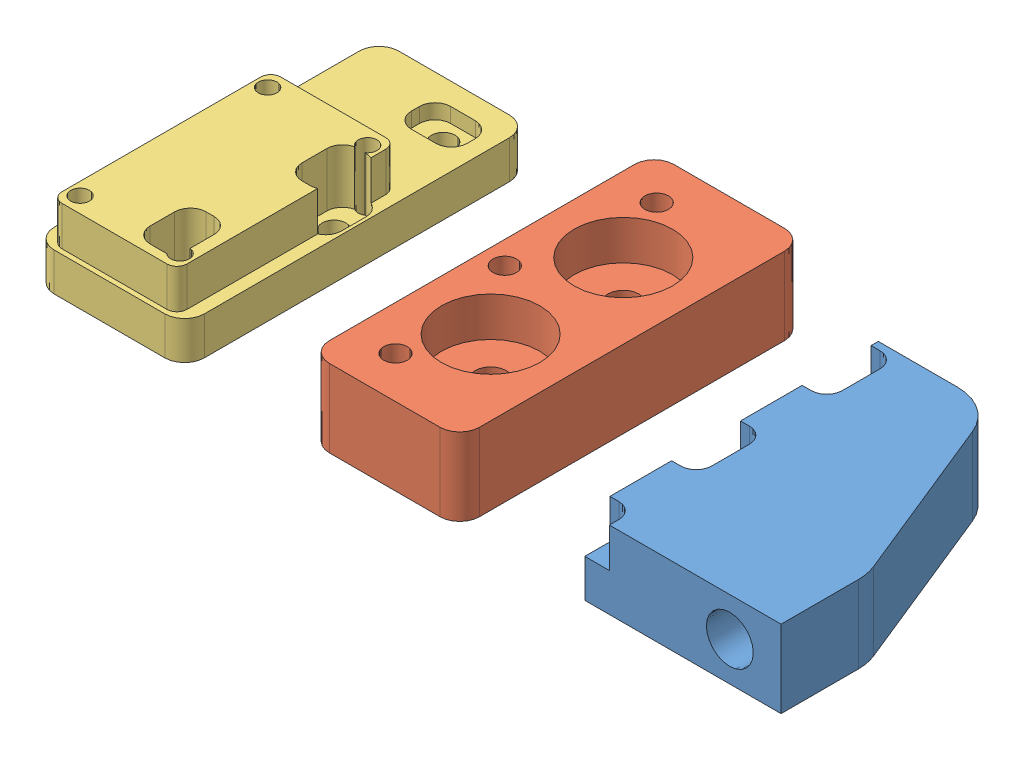
SolidWorks assembly Layout for Milling, configuration Default. Lengths in mm.
Overall size (151.68 15.75 70).
3 component instances, 3 part files, 8 mates.
Components (placement in the parent):
- TripodMount-1: TripodMount [Default] at (-7.2274 -10.9528 11.255) size (39.88 15.75 59.63)
- HingeMount-1: HingeMount [Default] at (-32.6274 4.7952 11.255) x (-1 0 0) z (0 0 1) size (30.5 15.75 70)
- tabletHingeAdapter-1: tabletHingeAdapter [Default] at (-119.0274 -10.9528 11.255) size (30.5 15.75 70)
Mates (geometry in assembly coordinates):
- Coincident1: coincident aligned: plane of TripodMount-1 through (-7.2274 -10.9528 11.255) normal (0 -1 0); plane of HingeMount-1 through (-32.6274 -10.9528 11.255) normal (0 -1 0)
- Coincident2: coincident aligned: plane of TripodMount-1 through (-7.2274 -10.9528 11.255) normal (0 -1 0); plane of tabletHingeAdapter-1 through (-119.0274 -10.9528 11.255) normal (0 -1 0)
- Parallel1: parallel aligned: plane of HingeMount-1 through (-32.6274 -10.9528 11.255) normal (1 0 0); plane of tabletHingeAdapter-1 through (-88.5274 4.7952 11.255) normal (1 0 0)
- Parallel2: parallel aligned: plane of TripodMount-1 through (32.6506 4.7952 -6.4453) normal (1 0 0); plane of tabletHingeAdapter-1 through (-88.5274 4.7952 11.255) normal (1 0 0)
- Coincident4: coincident aligned: plane of TripodMount-1 through (32.6506 4.7952 11.255) normal (0 0 1); plane of tabletHingeAdapter-1 through (-119.0274 4.7952 11.255) normal (0 0 1)
- Coincident5: coincident aligned: plane of TripodMount-1 through (32.6506 4.7952 11.255) normal (0 0 1); plane of HingeMount-1 through (-32.6274 -10.9528 11.255) normal (0 0 1)
- Distance2: distance = 25.4 mm anti-aligned: plane of HingeMount-1 through (-32.6274 -10.9528 11.255) normal (1 0 0); plane of TripodMount-1 through (-7.2274 4.7952 11.255) normal (-1 0 0)
- Distance3: distance = 25.4 mm anti-aligned: plane of HingeMount-1 through (-63.1274 -10.9528 11.255) normal (-1 0 0); plane of tabletHingeAdapter-1 through (-88.5274 4.7952 11.255) normal (1 0 0)
